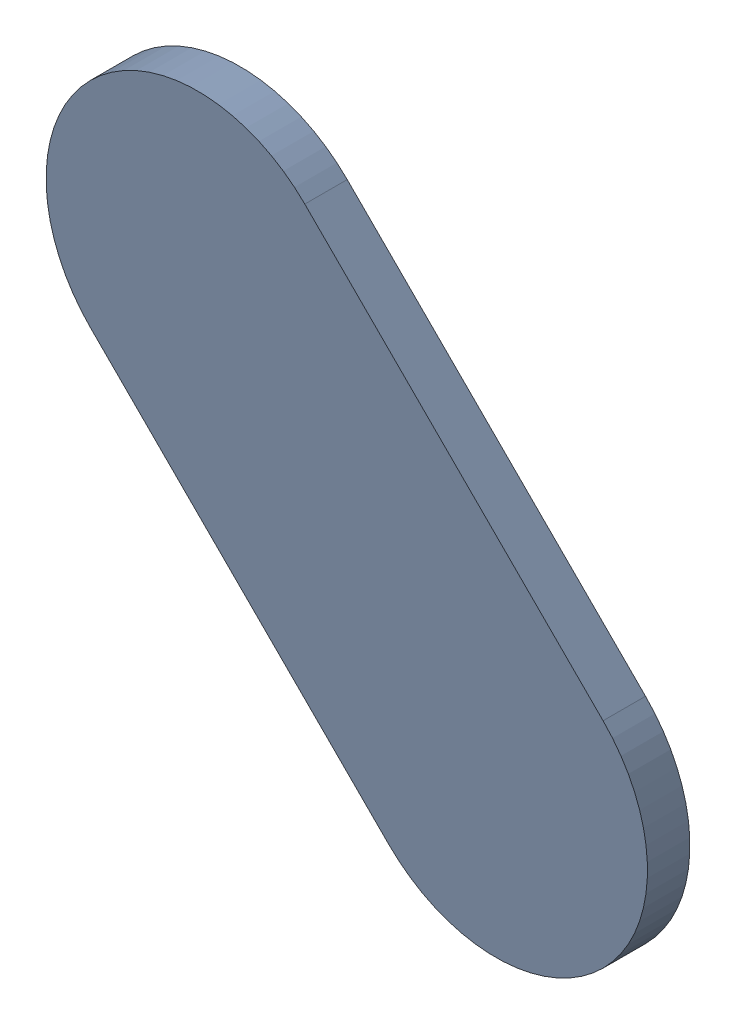
SolidWorks assembly Track (27.8mm,42.4mm)(28.05mm,42.15mm) on Top Layer, configuration Predeterminado. Lengths in mm.
Overall size (0.5 0.5 0.04).
2 component instances, 1 part files, 0 mates.
Components (placement in the parent):
- Track (27.8mm,42.4mm)(28.05mm,42.15mm) on Top Layer-1-1: Track (27.8mm,42.4mm)(28.05mm,42.15mm) on Top Layer-1 [Predeterminado] at (-68.317 -44.187 -0.0457) size (0.5 0.5 0.04)
  - Track (27.8mm,42.4mm)(28.05mm,42.15mm) on Top Layer-Part-1-1: Track (27.8mm,42.4mm)(28.05mm,42.15mm) on Top Layer-Part-1 [Predeterminado] at origin size (0.5 0.5 0.04)
